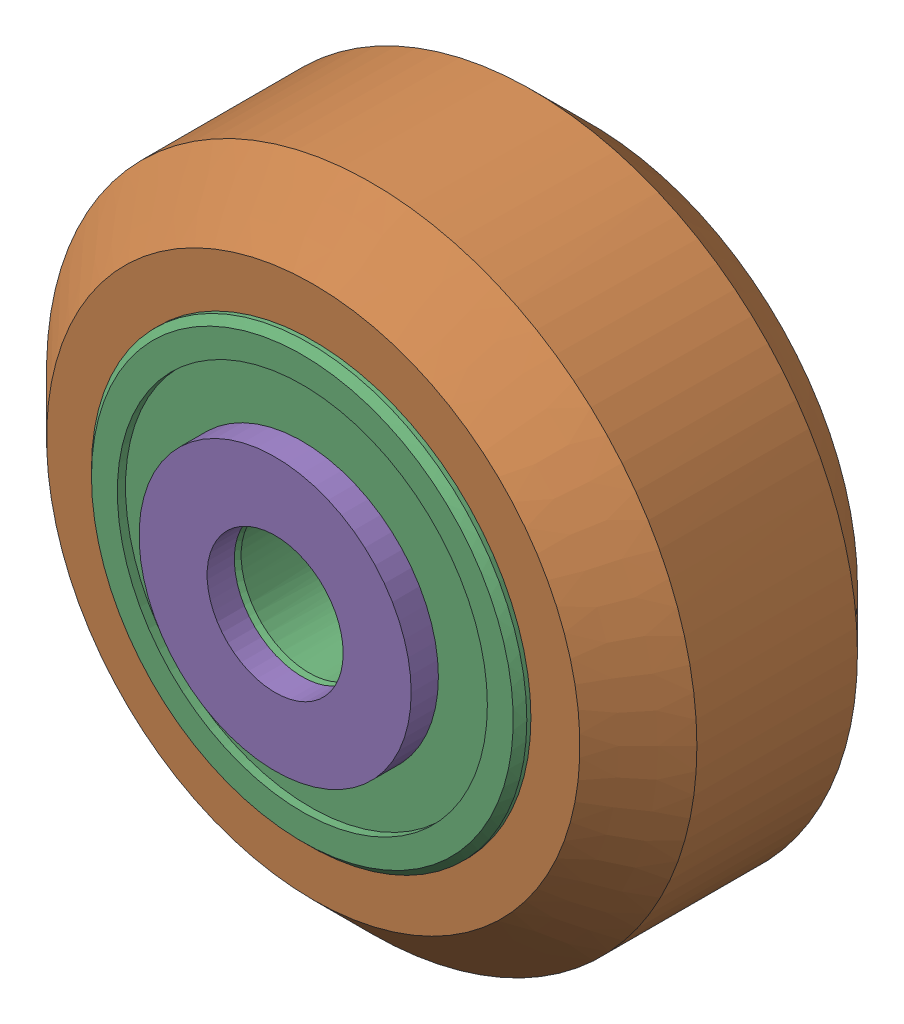
SolidWorks assembly Xtreme Solid V Wheel Kit Assembly_4, configuration Default. Lengths in mm.
Overall size (23.9 23.9 13).
6 component instances, 3 part files, 0 mates.
Components (placement in the parent):
- Precision Shim - 10x5x1mm-1: Precision Shim - 10x5x1mm [Default] at origin size (10 10 1)
- Xtreme Solid V Wheel Assembly_4-1: Xtreme Solid V Wheel Assembly_4 [Default] at (84.85 25.79 -23.5) size (23.9 23.9 11)
  - Xtreme Solid V Wheel-1: Xtreme Solid V Wheel [Default] at (-84.85 -25.79 30) x (0 0 1) z (-1 0 0) size (10.2 23.9 23.9)
  - Wheel+Kit+-+5x16x5mm+Sealed+Radial+Ball+Bearing.step.f3d-1: Wheel+Kit+-+5x16x5mm+Sealed+Radial+Ball+Bearing.step.f3d [Default] at (-84.85 -25.79 30) x (0 1 0) z (-1 0 0) size (16 5 16)
  - Wheel+Kit+-+5x16x5mm+Sealed+Radial+Ball+Bearing.step.f3d-2: Wheel+Kit+-+5x16x5mm+Sealed+Radial+Ball+Bearing.step.f3d [Default] at (-84.85 -25.79 30) x (0 1 0) z (1 0 0) size (16 5 16)
- Precision Shim - 10x5x1mm-2: Precision Shim - 10x5x1mm [Default] at (0 0 12) size (10 10 1)
